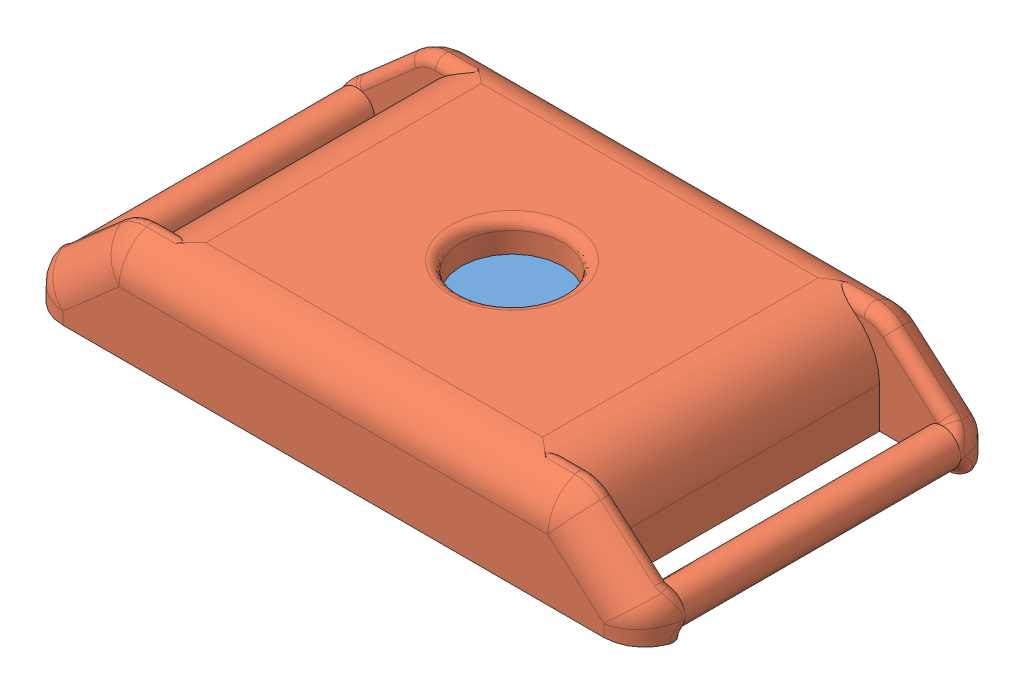
SolidWorks assembly Ensamblaje1, configuration Predeterminado. Lengths in mm.
Overall size (61.32 11 35).
2 component instances, 2 part files, 3 mates.
Components (placement in the parent):
- case 3 inferior-1: case 3 inferior [Predeterminado] at (-22.4028 -3.2044 27.5) size (45 3 35)
- case 3 superior-1: case 3 superior [Predeterminado] at (-22.4028 -2.2044 27.5) size (61.32 10 35)
Mates (geometry in assembly coordinates):
- Coincidente2: coincident: plane of assembly; plane of assembly; plane of case 3 inferior-1 through (-22.4028 -2.2044 61.5) normal (0 0 1); plane of case 3 superior-1 through (21.5972 4.7956 61.5) normal (0 0 -1)
- Coincidente3: coincident: plane of assembly; plane of assembly; plane of case 3 inferior-1 through (-21.4028 -2.2044 27.5) normal (-1 0 0); plane of case 3 superior-1 through (-21.4028 4.7956 28.5) normal (1 0 0)
- Coincidente4: coincident: plane of assembly; plane of assembly; plane of case 3 inferior-1 through (-22.4028 -2.2044 27.5) normal (0 1 0); plane of case 3 superior-1 through (-22.4028 -2.2044 62.5) normal (0 -1 0)
